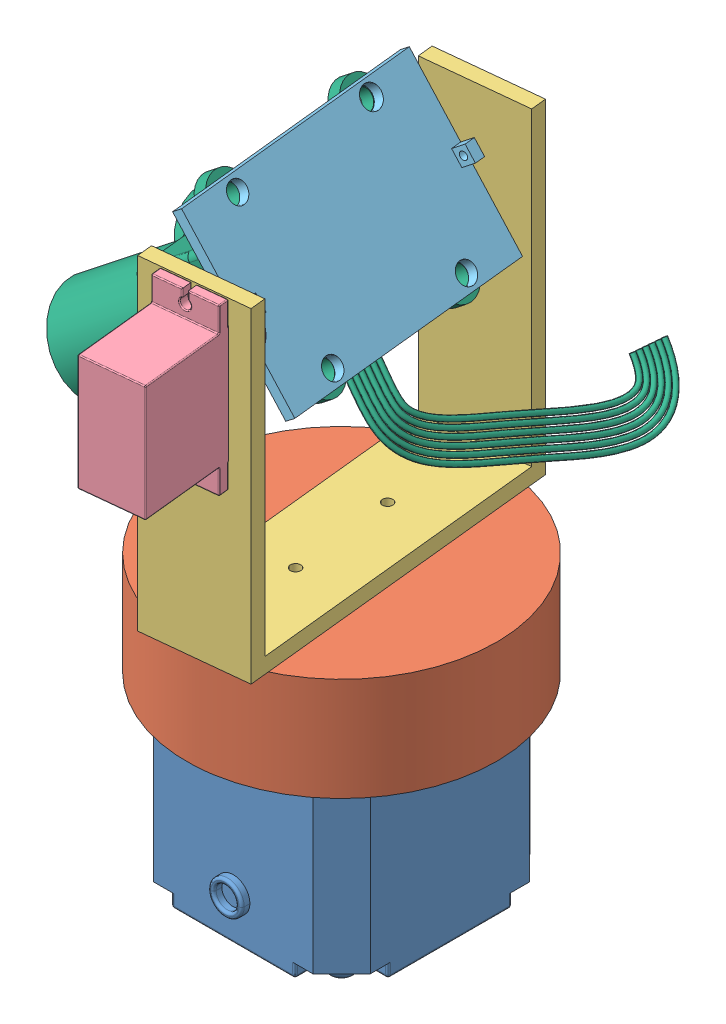
SolidWorks assembly new assem, configuration Default. Lengths in mm.
Overall size (85.98 121.11 106.78).
6 component instances, 6 part files, 14 mates.
Components (placement in the parent):
- stepper motor from datasheet-2: stepper motor from datasheet [Default] at (-5.9351 40.0569 49.5075) x (-1 0 0) z (0 1 0) size (42.06 43.63 53.04)
- gear-1: gear [Default] at (-5.9351 62.0569 49.5075) x (0.10359 0 0.99462) z (0 -1 0) size (60 60 20)
- uclamp-1: uclamp [Default] at (-18.8854 65.0569 21.6994) x (0.10359 0 0.99462) z (-0.99462 0 0.10359) size (64 63 20)
- ServoMotor-1: ServoMotor [Default] at (-2.4131 108.8569 83.3246) x (0 -1 0) z (0.99462 0 -0.10359) size (32 29 12)
- lidarbase-1: lidarbase [Default] at (-13.6193 117.0166 39.5253) x (-0.10359 0 -0.99462) z (0.791781 0.605213 -0.082464) size (49.5 33 5)
- Lidar-Lite-V3-1: Lidar-Lite-V3 [Default] at (-11.0937 110.4372 46.29) x (-0.102855 -0.000971 -0.994696) z (-0.602083 0.796063 0.061481) size (74.48 42.89 67.86)
Mates (geometry in assembly coordinates):
- Coincident1: coincident: plane of stepper motor from datasheet-2 through (5.0649 42.0569 38.2875) normal (0 1 0); plane of gear-1 through (-5.9351 42.0569 49.5075) normal (0 -1 0)
- Concentric1: concentric: circle of ?
- Concentric2: concentric: cylinder of gear-1 through (-6.2319 42.0569 39.5119) axis (0 1 0) radius 1; cylinder of uclamp-1 through (-6.2319 55.0569 39.5119) axis (0 1 0) radius 1
- Coincident7: coincident: plane of gear-1 through (-5.9351 62.0569 49.5075) normal (0 1 0); plane of uclamp-1 through (5.01 62.0569 81.1967) normal (0 -1 0)
- Concentric3: concentric: cylinder of gear-1 through (-5.6384 42.0569 59.5031) axis (0 1 0) radius 1; cylinder of uclamp-1 through (-5.6384 55.0569 59.5031) axis (0 1 0) radius 1
- Coincident8: coincident: plane of uclamp-1 through (-5.2823 97.6069 71.4978) normal (0 1 0); plane of ServoMotor-1 through (-10.4488 97.6069 99.6635) normal (0 -1 0)
- Coincident9: coincident: plane of uclamp-1 through (0.715 120.4229 71.3197) normal (-0.99956 0 0.029674); plane of ServoMotor-1 through (1.5459 120.1069 99.3074) normal (0.99956 0 -0.029674)
- Coincident10: coincident: plane of uclamp-1 through (5.01 125.0569 81.1967) normal (0.029674 0 0.99956); plane of ServoMotor-1 through (-4.9856 122.4819 81.4934) normal (-0.029674 0 -0.99956)
- Concentric4: concentric: cylinder of ServoMotor-1 through (-5.1636 114.1069 75.496) axis (-0.029674 0 -0.99956) radius 0.75; cylinder of lidarbase-1 through (-7.3891 114.1069 0.5291) axis (0.029674 0 0.99956) radius 0.75
- Coincident11: coincident: plane of ServoMotor-1 through (-5.312 114.1069 70.4982) normal (-0.029674 0 -0.99956); plane of lidarbase-1 through (10.2603 108.4687 70.0359) normal (0.029674 0 0.99956)
- Coincident12: coincident: plane of lidarbase-1 through (0.9477 114.5984 38.574) normal (0.423849 0.905645 -0.012583); plane of Lidar-Lite-V3-1 through (-20.2058 124.9423 70.5228) normal (-0.423849 -0.905645 0.012583)
- Concentric5: concentric: cylinder of lidarbase-1 through (-21.2581 48.0061 60.7571) axis (0.423849 0.905645 -0.012583) radius 1.9558; cylinder of Lidar-Lite-V3-1 through (8.4113 111.4013 59.8763) axis (0.423849 0.905645 -0.012583) radius 1.9558
- Lock2: lock: unknown of lidarbase-1; unknown of Lidar-Lite-V3-1
- Parallel5: parallel: plane of uclamp-1 through (3.1999 65.0569 20.2235) normal (0.029674 0 0.99956); plane of lidarbase-1 through (8.7915 108.4687 20.5577) normal (-0.029674 0 -0.99956)
